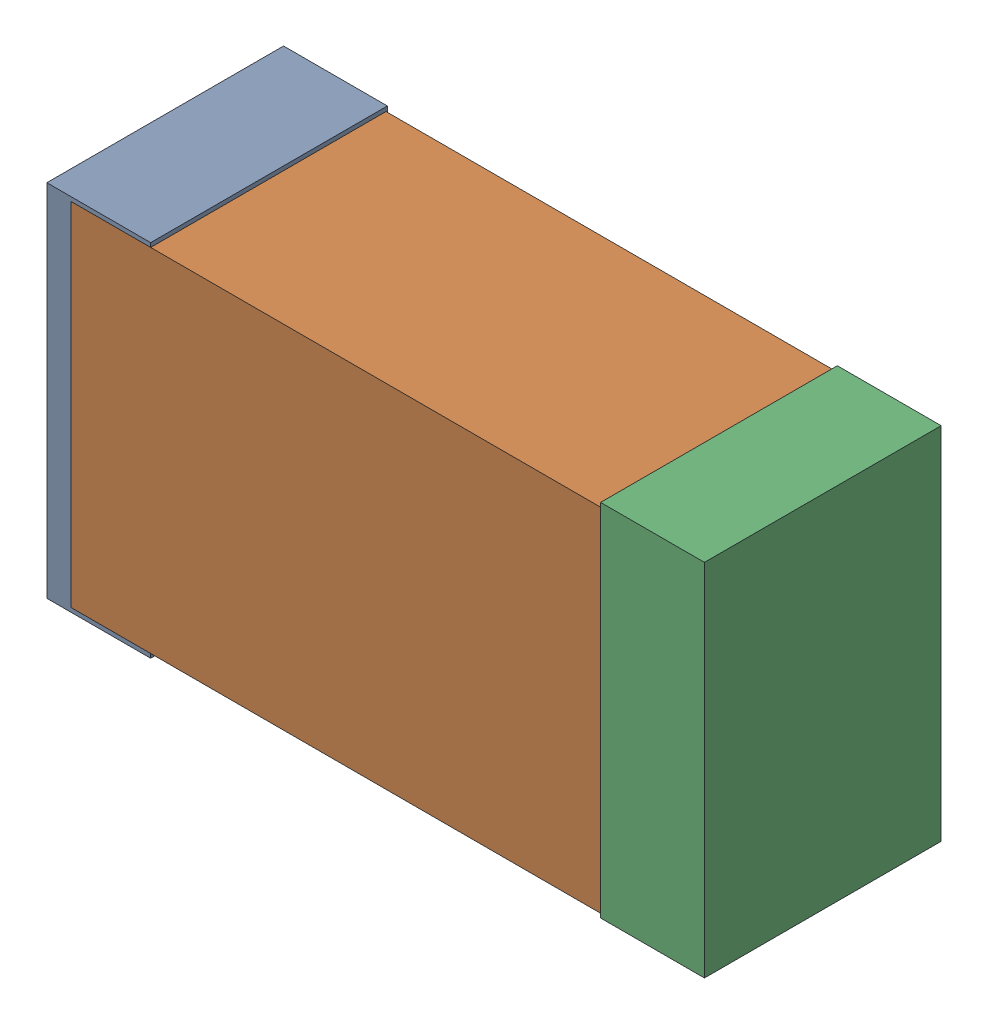
SolidWorks assembly USB45_C10, configuration Default. Lengths in mm.
Overall size (2.38 1.3 0.85).
6 component instances, 2 part files, 0 mates.
Components (placement in the parent):
- 384311232-1: 384311232 [Default] at (172.99 40.005 -1.9574) size (0.38 1.3 0.85)
  - Extruded_8-1: Extruded_8 [Default] at origin size (0.38 1.3 0.85)
- 384311360-1: 384311360 [Default] at (173.99 40.005 -1.9524) size (2.2 1.27 0.85)
  - Extruded_9-1: Extruded_9 [Default] at origin size (2.2 1.27 0.85)
- 384311232-2: 384311232 [Default] at (174.99 40.005 -1.9574) size (0.38 1.3 0.85)
  - Extruded_8-1: Extruded_8 [Default] at origin size (0.38 1.3 0.85)
